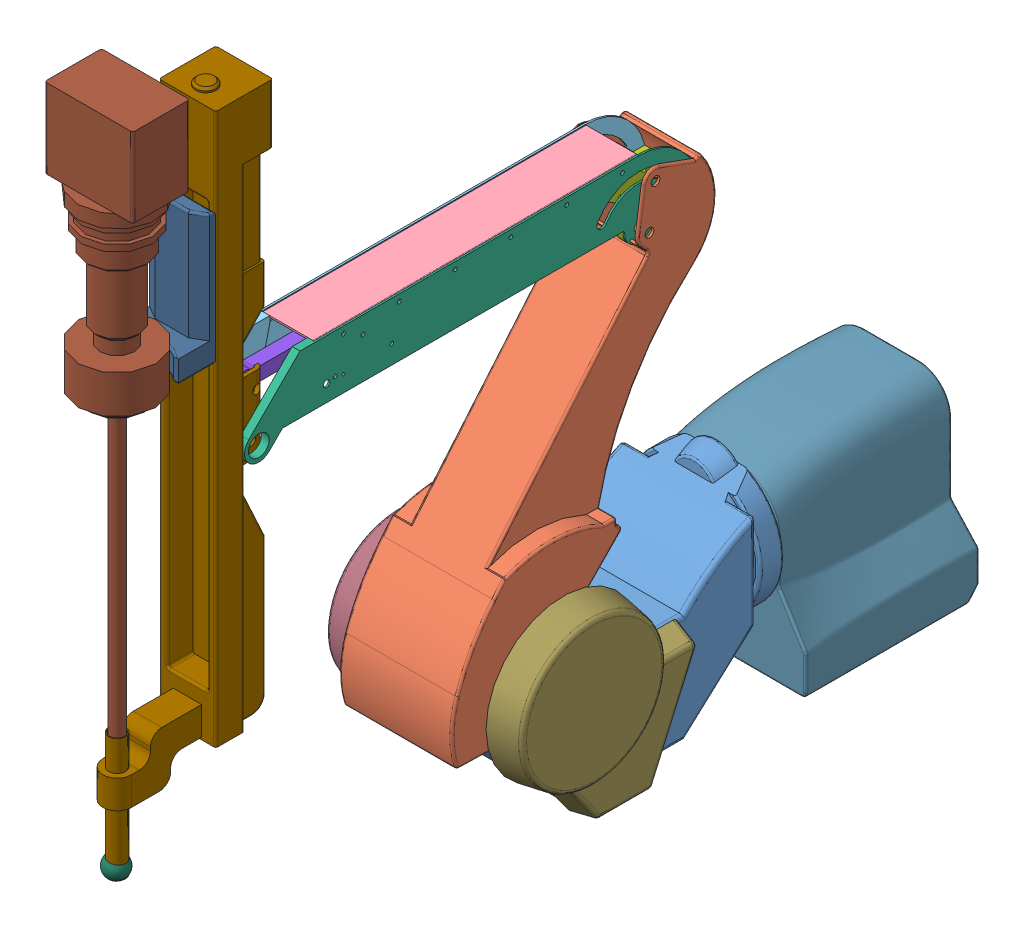
SolidWorks assembly ECM_Assem, configuration Default. Lengths in mm.
Overall size (176 704.97 742.83).
17 component instances, 15 part files, 30 mates.
Components (placement in the parent):
- ECM_yaw-1: ECM_yaw [Default] at (504.3366 98 -642.2718) size (120.46 160.6 250.19)
- ECM_1-1: ECM_1 [Default] at (554.8366 98 -444.2718) x (0 0.023853 0.999715) z (-1 0 0) size (246.13 367.75 101)
- ECM_Front-1: ECM_Front [Default] at (510.3341 98.853 -444.5155) x (0 -0.02384 -0.999716) z (1 0 0) size (116.32 309.18 59.5)
- ECM Link-1: ECM Link [Default] at (657.6933 539.4129 -179.7246) x (0 -1 0.000398) z (0 -0.000398 -1) size (73.78 49.67 408.25)
  - ECM Plate Aluminum - Top-1: ECM Plate Aluminum - Top [Default] at (100.2114 153.3593 78.0369) size (10 46.5 289.77)
  - ECM Plate Aluminum - Right-1: ECM Plate Aluminum - Right [Default] at (154.4614 178.1968 27.2095) x (0 0 1) z (0 -1 0) size (408.25 73.78 8.63)
  - ECM Plate Aluminum - Left-2: ECM Plate Aluminum - Left [Default] at (154.4614 130.1093 27.2095) x (0 0 1) z (0 -1 0) size (408.25 73.78 7.04)
  - Lower Joint Reinforcer-1: Lower Joint Reinforcer [Default] at (154.4614 136.4593 27.0096) x (0 0 1) z (0 -1 0) size (67.5 31.28 6.35)
  - Lower Joint Reinforcer-2: Lower Joint Reinforcer [Default] at (154.4614 176.6093 27.0096) x (0 0 1) z (0 -1 0) size (67.5 31.28 6.35)
- ECM_top-1: ECM_top [Default] at (511.1291 422.2574 -552.7441) x (0 0.000398 1) z (-1 0 0) size (358.4 18 12)
- ECM_3-1: ECM_3 [Default] at (530.6291 90.0166 -444.1759) x (0 0.023851 0.999716) z (-1 0 0) size (128.48 578.63 51)
- ECM_insertion-1: ECM_insertion [Default] at (505.1291 98.9813 -444.1749) x (0 0.023954 0.999713) z (-1 0 0) size (33.68 118.66 54)
- ECM_Tool-1: ECM_Tool [Default] at (505.1291 89.9813 -444.175) x (0 0.023954 0.999713) z (-1 0 0) size (73.26 603.23 79)
- ECM_yaw_cover-1: ECM_yaw_cover [Default] at (564.3366 98 -642.2718) size (28 170.08 171.49)
- ECM_yaw_cover Mirror-1: ECM_yaw_cover Mirror [Default] at (444.3366 98 -642.2718) size (28 170.08 171.49)
- ECM_Base-1: ECM_Base [Default] at (425.7566 -3.46 -798.8468) size (165.2 163.16 155.71)
- ECM_RCM-1: ECM_RCM [Default] at (504.3366 98.1353 -103.8726) x (-0.606083 0 0.795402) z (-0.795402 0 -0.606083) size (20 20 20)
Mates (geometry in assembly coordinates):
- Concentric1: concentric aligned: cylinder of ECM_yaw-1 through (575.6503 98 -444.2718) axis (-1 0 0) radius 4; cylinder of ECM_1-1 through (554.8366 98 -444.2718) axis (-1 0 0) radius 4
- Distance2: distance = 1.5 mm anti-aligned: plane of ECM_yaw-1 through (452.3366 98 -444.2718) normal (1 0 0); plane of ECM_1-1 through (453.8366 98 -444.2718) normal (-1 0 0)
- Distance3: distance = 10.9 mm anti-aligned: plane of ECM_Front-1 through (498.3341 102.98 -433.0232) normal (-1 0 0); plane of ECM Link-1/Lower Joint Reinforcer-2 through (487.4341 384.9407 -206.6727) normal (1 0 0)
- Distance4: distance = 7.66 mm anti-aligned: plane of ECM_1-1 through (471.8366 98 -444.2718) normal (1 0 0); plane of ECM Link-1/ECM Plate Aluminum - Right-1 through (479.4966 384.9406 -206.8726) normal (-1 0 0)
- Concentric6: concentric anti-aligned: cylinder of ECM_1-1 through (554.8366 422.2574 -552.7441) axis (-1 0 0) radius 4; cylinder of ECM_top-1 through (499.1291 422.2574 -552.7441) axis (1 0 0) radius 4
- Concentric7: concentric aligned: cylinder of ECM_top-1 through (499.1291 422.3931 -212.344) axis (1 0 0) radius 4; cylinder of ECM_3-1 through (479.6291 422.3931 -212.344) axis (1 0 0) radius 4
- Coincident3: coincident anti-aligned: plane of ECM Link-1/ECM Plate Aluminum - Right-1; plane of ECM_3-1
- Concentric9: concentric aligned: cylinder of ECM_3-1 through (505.1291 202.2406 -103.8726) axis (0 -1 0) radius 7.5; cylinder of ECM_insertion-1 through (505.1291 525.0839 -103.8726) axis (0 -1 0) radius 36
- Parallel1: parallel anti-aligned: plane of ECM_3-1 through (479.6291 90.0166 -166.8726) normal (0 0 1); plane of ECM_insertion-1 through (532.1291 98.9813 -164.8726) normal (0 0 -1)
- Concentric10: concentric aligned: cylinder of ECM_insertion-1 through (505.1291 525.0839 -103.8726) axis (0 -1 0) radius 36; cylinder of ECM_Tool-1 through (505.1291 97.4353 -103.8726) axis (0 -1 0) radius 34.5
- Coincident4: coincident aligned: plane of ECM_insertion-1 through (532.1291 471.0839 -444.1749) normal (0 -1 0); plane of ECM_Tool-1 through (505.1291 471.0839 -444.175) normal (0 -1 0)
- Distance6: distance = 6 mm anti-aligned: plane of ECM_top-1 through (499.1291 422.2574 -552.7441) normal (-1 0 0); plane of ECM_3-1 through (493.1291 314.7686 -214.6353) normal (1 0 0)
- Concentric11: concentric aligned: cylinder of ECM_yaw-1 through (575.6503 98 -444.2718) axis (-1 0 0) radius 4; circle of ECM_yaw_cover-1
- Coincident7: coincident: plane of ECM_yaw-1 through (564.3366 98 -444.2718) normal (1 0 0); line of ECM_yaw_cover-1 through (564.3366 -1.1128 -500.9918) axis (0 0 1)
- Concentric12: concentric aligned: circle of ECM_yaw-1; circle of ECM_yaw_cover Mirror-1
- Coincident8: coincident anti-aligned: plane of ECM_yaw-1 through (444.3366 98 -444.2718) normal (-1 0 0); plane of ECM_yaw_cover Mirror-1 through (444.3366 98 -642.2718) normal (1 0 0)
- Parallel4: parallel: plane of ECM_yaw-1 through (564.3366 0 -553.2718) normal (0 -1 0); line of ECM_yaw_cover-1 through (564.3366 -3.1437 -501.0316) axis (0 0 1)
- Parallel5: parallel: plane of ECM_yaw-1 through (564.3366 0 -553.2718) normal (0 -1 0); line of ECM_yaw_cover Mirror-1 through (444.3366 -3.1437 -501.0316) axis (0 0 1)
- Concentric13: concentric anti-aligned: circle of ECM_yaw-1; line of ECM_Base-1 through (504.3366 98 -643.2718) axis (0 0 1)
- Distance7: distance = 1 mm anti-aligned: plane of ECM_yaw-1 through (504.3366 98 -642.2718) normal (0 0 -1); plane of ECM_Base-1 through (431.7566 29.8379 -643.2718) normal (0 0 1)
- zero_yaw: planar angle = 0 rad anti-aligned: plane of ECM_Base-1 through (425.7566 -3.46 -798.8468) normal (0 1 0); plane of ECM_yaw-1
- Pitch_0: parallel anti-aligned: plane of ECM_yaw-1 through (504.3366 98 -642.2718) normal (0 0 -1); plane of ECM_3-1 through (479.6291 90.0166 -166.8726) normal (0 0 1)
- insertion_zero: distance = 0.7 mm: plane of ECM_Tool-1; point of ECM_3-1
- rotation_zero: planar angle = 0 rad aligned: plane of ECM_3-1 through (478.8872 103.1502 -166.8726) normal (0 0 1); plane of ECM_Tool-1 through (765.8808 642.1487 -78.3726) normal (0 0 1)
- Concentric15: concentric aligned: cylinder of ECM_1-1 through (554.8366 384.805 -547.2727) axis (-1 0 0) radius 4; cylinder of ECM Link-1/ECM Plate Aluminum - Left-2 through (529.1716 384.805 -547.2727) axis (-1 0 0) radius 4
- Concentric16: concentric anti-aligned: cylinder of ECM_yaw-1 through (575.6503 88.2 -480.8418) axis (-1 0 0) radius 4; cylinder of ECM_Front-1 through (480.3341 88.2 -480.8418) axis (1 0 0) radius 4
- Concentric17: concentric anti-aligned: cylinder of ECM_Front-1 through (480.3341 375.0063 -583.8375) axis (1 0 0) radius 4; cylinder of ECM Link-1/ECM Plate Aluminum - Right-1 through (481.0841 375.0063 -583.8375) axis (-1 0 0) radius 3
- Concentric18: concentric anti-aligned: cylinder of ECM Link-1/ECM Plate Aluminum - Right-1 through (488.1291 384.9406 -206.8726) axis (-1 0 0) radius 9.3; cylinder of ECM_3-1 through (479.6291 384.9406 -206.8726) axis (1 0 0) radius 4
- Coincident10: coincident anti-aligned: line of ECM_RCM-1 through (504.3366 108.1353 -103.8726) axis (0 -1 0); line of assembly
- Coincident12: coincident: point of ECM_RCM-1; line of assembly
